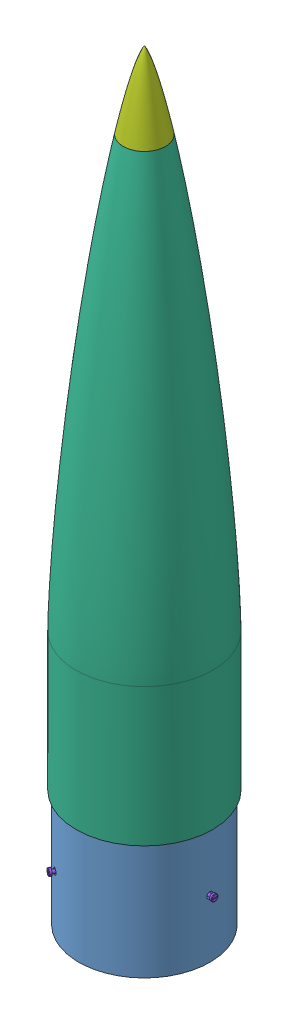
SolidWorks assembly S1A_Nose_Cone, configuration Default. Lengths in mm.
Overall size (80.74 442.25 79.45).
10 component instances, 8 part files, 24 mates.
Components (placement in the parent):
- S1A_Nose_Cone_Shoulder_Tube-1: S1A_Nose_Cone_Shoulder_Tube [Default] at origin size (76.28 147.82 76.28)
- S1A_Nose_Cone_Bulkhead-1: S1A_Nose_Cone_Bulkhead [Default] at (0 141.4653 0) size (73.03 6.35 73.03)
- S1A_Nose_Cone_Recovery_Eyebolt_3014T45_Steel Eyebolt with Shoulder - for Lifting-1: S1A_Nose_Cone_Recovery_Eyebolt_3014T45_Steel Eyebolt with Shoulder - for Lifting [3014T45] at (0 117.6528 0) x (-1 0 0) z (0 0 1) size (30.16 64.29 14.29)
- S1A_Nose_Cone_Recovery_Nut_95462A029_Medium-Strength Steel Hex Nut-1: S1A_Nose_Cone_Recovery_Nut_95462A029_Medium-Strength Steel Hex Nut [95462A029] at (0 151.6856 0) x (1 0 0) z (0 1 0) size (11.11 12.83 5.56)
- S1A_Nose_Cone_Recovery_Washer_90107A029_316 Stainless Steel Washer-1: S1A_Nose_Cone_Recovery_Washer_90107A029_316 Stainless Steel Washer [90107A029] at (0 147.8153 0) x (-1 0 0) z (0 0 -1) size (15.88 1.09 15.88)
- S1A_Nose_Cone-1: S1A_Nose_Cone [Default] at (0 442.2522 0) x (0 -1 0) z (0 0 -1) size (330.2 79.45 79.45)
- S1A_Nose_Cone_Tip-1: S1A_Nose_Cone_Tip [Default] at (0 442.2521 0) x (0 -1 0) z (0 0 1) size (44.45 24.48 24.48)
- S1A_Shear_Pin-1: S1A_Shear_Pin [Default] at (39.7256 33.8074 0) x (0 -1 0) z (-1 0 0) size (3.81 3.83 10.38)
- S1A_Shear_Pin-2: S1A_Shear_Pin [Default] at (-19.8628 33.8074 -34.4034) x (0 -1 0) z (0.5 0 0.866025) size (3.81 3.83 10.38)
- S1A_Shear_Pin-3: S1A_Shear_Pin [Default] at (-19.8628 33.8074 34.4034) x (0 -1 0) z (0.5 0 -0.866025) size (3.81 3.83 10.38)
Mates (geometry in assembly coordinates):
- Coincident1: coincident anti-aligned: line of S1A_Nose_Cone_Shoulder_Tube-1 through (162.4711 0 155.0861) axis (0 0 -1)
- Coincident2: coincident aligned: plane of S1A_Nose_Cone_Shoulder_Tube-1 through (0 0 0) normal (0 1 0)
- Coincident3: coincident aligned: plane of S1A_Nose_Cone_Shoulder_Tube-1 through (0 0 0) normal (0 0 1)
- Coincident4: coincident aligned: line of S1A_Nose_Cone_Bulkhead-1 through (6.985 0 141.1478) axis (0 0 1)
- Parallel1: parallel aligned: plane of S1A_Nose_Cone_Bulkhead-1 through (0 141.4653 0) normal (0 0 1)
- Distance1: distance = 0 mm aligned: plane of S1A_Nose_Cone_Bulkhead-1 through (0 147.8153 0) normal (0 1 0); plane of S1A_Nose_Cone_Shoulder_Tube-1 through (0 147.8153 0) normal (0 1 0)
- Coincident5: coincident anti-aligned: line of S1A_Nose_Cone_Recovery_Eyebolt_3014T45_Steel Eyebolt with Shoulder - for Lifting-1 through (70.7231 0 170.08) axis (0 0 -1)
- Parallel2: parallel aligned: plane of S1A_Nose_Cone_Recovery_Eyebolt_3014T45_Steel Eyebolt with Shoulder - for Lifting-1 through (0 117.6528 0) normal (0 0 1)
- Coincident6: coincident anti-aligned: plane of S1A_Nose_Cone_Bulkhead-1 through (0 141.4653 0) normal (0 -1 0); plane of S1A_Nose_Cone_Recovery_Eyebolt_3014T45_Steel Eyebolt with Shoulder - for Lifting-1 through (6.4492 141.4653 0) normal (0 1 0)
- Coincident7: coincident anti-aligned: line of S1A_Nose_Cone_Recovery_Nut_95462A029_Medium-Strength Steel Hex Nut-1 through (6.1119 0 154.7416) axis (0 0 -1)
- Parallel3: parallel anti-aligned: plane of S1A_Nose_Cone_Recovery_Nut_95462A029_Medium-Strength Steel Hex Nut-1 through (0 151.6856 0) normal (0 0 -1)
- Coincident9: coincident aligned: line of S1A_Nose_Cone_Recovery_Washer_90107A029_316 Stainless Steel Washer-1 through (1.2014 0 147.7607) axis (0 0 1)
- Coincident10: coincident anti-aligned: plane of S1A_Nose_Cone_Bulkhead-1 through (0 147.8153 0) normal (0 1 0); plane of S1A_Nose_Cone_Recovery_Washer_90107A029_316 Stainless Steel Washer-1 through (0 147.8153 0) normal (0 -1 0)
- Parallel4: parallel anti-aligned: plane of S1A_Nose_Cone_Recovery_Washer_90107A029_316 Stainless Steel Washer-1 through (0 147.8153 0) normal (0 0 -1)
- Coincident11: coincident anti-aligned: plane of S1A_Nose_Cone_Recovery_Nut_95462A029_Medium-Strength Steel Hex Nut-1 through (-5.5563 148.9075 -3.2079) normal (0 -1 0); plane of S1A_Nose_Cone_Recovery_Washer_90107A029_316 Stainless Steel Washer-1 through (0 148.9075 0) normal (0 1 0)
- Parallel7: parallel aligned: plane of S1A_Nose_Cone_Tip-1 through (0 442.2521 0) normal (0 0 1)
- Coincident17: coincident aligned: line of S1A_Nose_Cone_Tip-1 through (48.895 0 395.5796) axis (0 0 1)
- Coincident18: coincident anti-aligned: line of S1A_Nose_Cone-1 through (0 461.3022 0) axis (0 -1 0)
- Parallel8: parallel anti-aligned: plane of S1A_Nose_Cone-1 through (0 442.2522 0) normal (0 0 -1)
- Coincident19: coincident anti-aligned: plane of S1A_Nose_Cone_Shoulder_Tube-1 through (0 147.8153 0) normal (0 1 0); plane of S1A_Nose_Cone-1 through (0 147.8153 0) normal (0 -1 0)
- Coincident20: coincident aligned: plane of S1A_Nose_Cone-1 through (0 397.8021 0) normal (0 -1 0); plane of S1A_Nose_Cone_Tip-1 through (0 397.8021 0) normal (0 -1 0)
- Concentric1: concentric anti-aligned: cylinder of S1A_Nose_Cone_Shoulder_Tube-1 through (-38.1391 33.8074 0) axis (1 0 0) radius 1.7859; cylinder of S1A_Shear_Pin-1 through (-15.2744 33.8074 0) axis (-1 0 0) radius 0.9906
- Coincident21: coincident anti-aligned: plane of S1A_Shear_Pin-1 through (39.7256 33.8074 1.905) normal (-1 0 0)
- Parallel9: parallel aligned: plane of S1A_Shear_Pin-1 through (40.7416 33.6804 0) normal (0 1 0)
